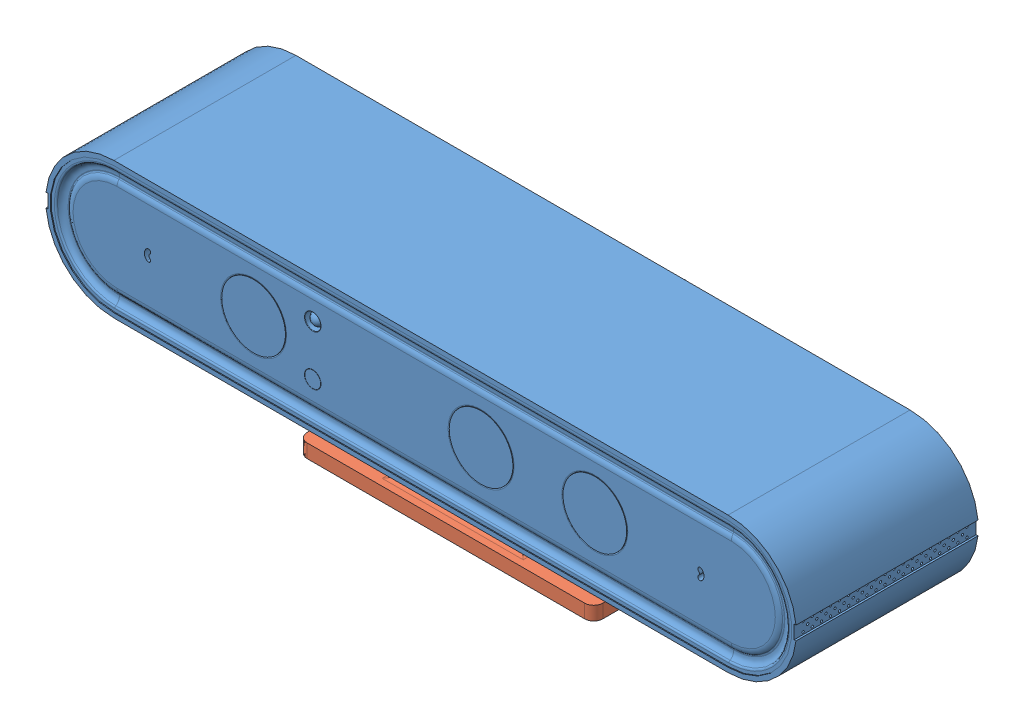
SolidWorks assembly HEL-03-01011-00, configuration 15°. Lengths in mm.
Overall size (164.85 41 58.1).
10 component instances, 4 part files, 12 mates.
Components (placement in the parent):
- HEL-06-01006-00-1: HEL-06-01006-00 [Standard] at (0 26 5.4655)
- HEL-04-01013-02-1: HEL-04-01013-02 [Standard] at origin
- HEL-04-01013-01-1: HEL-04-01013-01 [Standard] at origin (suppressed, hidden)
- Thread Insert MULTISERT 003M3-2: Thread Insert MULTISERT 003M3 [Standard] at (22.5 5.2 -44) x (-0.999795 0 0.02023) z (0.02023 0 0.999795)
- Thread Insert MULTISERT 003M3-3: Thread Insert MULTISERT 003M3 [Standard] at (22.5 5.2 -19) x (-0.999795 0 0.02023) z (0.02023 0 0.999795)
- Thread Insert MULTISERT 003M3-4: Thread Insert MULTISERT 003M3 [Standard] at (-22.5 5.2 -44) x (-0.999795 0 0.02023) z (0.02023 0 0.999795)
- Thread Insert MULTISERT 003M3-5: Thread Insert MULTISERT 003M3 [Standard] at (-22.5 5.2 -19) x (-0.999795 0 0.02023) z (0.02023 0 0.999795)
- Thread Insert MULTISERT 003M3-6: Thread Insert MULTISERT 003M3 [Standard] at (22.5 5.2 -21) x (-0.999795 0 0.02023) z (0.02023 0 0.999795) (suppressed, hidden)
- Thread Insert MULTISERT 003M3-7: Thread Insert MULTISERT 003M3 [Standard] at (-22.5 5.2 -46) x (-0.999795 0 0.02023) z (0.02023 0 0.999795) (suppressed, hidden)
- Thread Insert MULTISERT 003M3-8: Thread Insert MULTISERT 003M3 [Standard] at (-22.5 5.2 -21) x (-0.999795 0 0.02023) z (0.02023 0 0.999795) (suppressed, hidden)
Mates (geometry in assembly coordinates):
- Parallel1: parallel aligned: plane of HEL-06-01006-00-1 through (0 26 5.4655) normal (0 0 1); plane of HEL-04-01013-01-1 through (13 3 -5.8933) normal (0 0 1)
- Deckungsgleich4: coincident aligned: plane of HEL-06-01006-00-1 through (0 26 5.4655) normal (1 0 0)
- Deckungsgleich7: coincident anti-aligned: plane of HEL-04-01013-00-1 through (0 4 0) normal (0 1 0); plane of HEL-06-01006-00-1 through (0 6 5.4655) normal (0 -1 0)
- Parallel2: parallel aligned: plane of HEL-06-01006-00-1 through (0 26 5.4655) normal (0 0 1); plane of HEL-04-01013-02-1 through (13 3 -4) normal (0 0 1)
- Deckungsgleich10: coincident anti-aligned: plane of HEL-06-01006-00-1 through (0 6 5.4655) normal (0 -1 0); plane of HEL-04-01013-02-1 through (0 6 0) normal (0 1 0)
- Abstand4: distance = 1 mm: plane of HEL-04-01013-02-1 through (13 3 -4) normal (0 0 1); point of HEL-06-01006-00-1
- Deckungsgleich11: coincident anti-aligned: plane of HEL-06-01006-00-1 through (0 6 3.5722) normal (0 -1 0); plane of HEL-04-01013-01-1 through (0 6 0) normal (0 1 0)
- Abstand5: distance = 1 mm: point of HEL-06-01006-00-1; plane of HEL-04-01013-01-1 through (13 3 -5.8933) normal (0 0 1)
- Konzentrisch1: concentric anti-aligned: cylinder of HEL-04-01013-02-1 through (22.5 0 -44) axis (0 -1 0) radius 2.45; cylinder of HEL-06-01009-00-2 through (22.5 0.3 -44) axis (0 1 0) radius 2
- Deckungsgleich12: coincident aligned: plane of HEL-04-01013-02-1 through (0 0 0) normal (0 -1 0); plane of HEL-06-01009-00-2 through (22.5 0 -44) normal (0 -1 0)
- Konzentrisch2: concentric anti-aligned: cylinder of HEL-04-01013-01-1 through (22.5 0 -46) axis (0 -1 0) radius 2; cylinder of HEL-06-01009-00-2 through (22.5 0.3 -46) axis (0 1 0) radius 2
- Deckungsgleich13: coincident aligned: plane of HEL-04-01013-01-1 through (0 0 -559.0561) normal (0 -1 0); plane of HEL-06-01009-00-2 through (22.5 0 -46) normal (0 -1 0)
